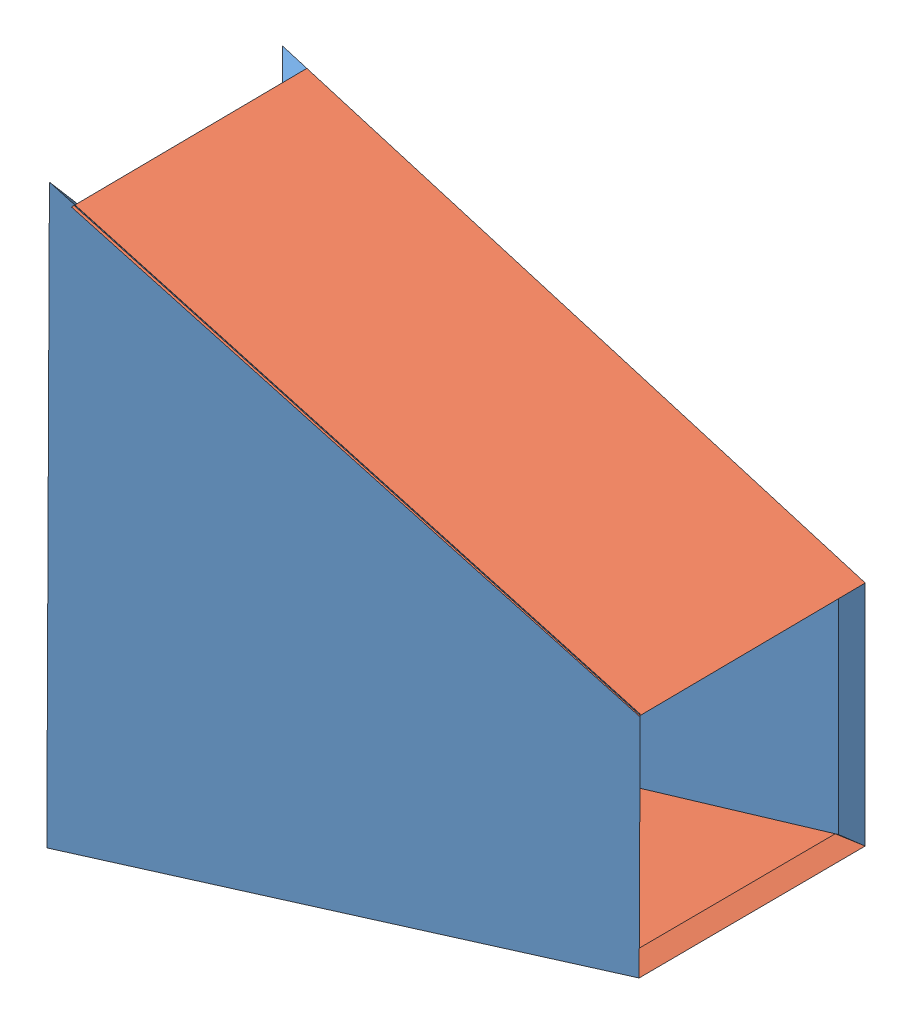
SolidWorks assembly Baugruppe2, configuration Standard. Lengths in mm.
Overall size (436.05 429.6 180.8).
4 component instances, 2 part files, 8 mates.
Components (placement in the parent):
- Gehäseseite1-2: Gehäseseite1 [Standard] at (252.3997 -5.8404 429.7143) size (434.71 429.2 10)
- Gehäseseite2-2: Gehäseseite2 [Standard] at (253.0555 78.9641 514.7116) x (0.958288 -0.285691 -0.008051) z (-0.285701 -0.958319 0) size (434.71 177 10)
- Gehäseseite2-3: Gehäseseite2 [Standard] at (253.0555 -90.6449 514.7116) x (0.958288 0.285691 -0.008051) z (-0.285701 0.958319 0) size (434.71 177 10)
- Gehäseseite1-3: Gehäseseite1 [Standard] at (253.7083 -5.4503 599.3178) x (0.999881 -0.000035 -0.01543) z (-0.01543 -0.0046 -0.99987) size (434.71 429.2 10)
Mates (geometry in assembly coordinates):
- Deckungsgleich13: coincident: line of Gehäseseite1-2 through (252.3997 79.1596 429.7143) axis (-0.958319 0.285701 0); line of Gehäseseite2-2 through (-164.2088 203.3617 429.7143) axis (0.958319 -0.285701 0)
- Deckungsgleich14: coincident: point of Gehäseseite1-2; point of Gehäseseite2-2
- Deckungsgleich15: coincident: line of Gehäseseite1-2 through (-182.3146 -220.4404 429.7143) axis (0.958319 0.285701 0); line of Gehäseseite2-3 through (252.3997 -90.8404 429.7143) axis (-0.958319 -0.285701 0)
- Deckungsgleich16: coincident: line of Gehäseseite1-2 through (-172.3146 -207.0242 439.7143) axis (0.958319 0.285701 0); line of Gehäseseite2-3 through (240.0364 -84.0913 439.7143) axis (-0.958319 -0.285701 0)
- Deckungsgleich17: coincident: point of Gehäseseite1-2; point of Gehäseseite2-3
- Deckungsgleich19: coincident: line of Gehäseseite2-3 through (-162.8431 -214.6355 606.7086) axis (0.958195 0.285664 -0.016101); line of Gehäseseite1-3 through (253.7113 -90.4494 599.7088) axis (-0.958195 -0.285664 0.016101)
- Deckungsgleich20: coincident: line of Gehäseseite2-3 through (-156.195 -202.2185 596.5476) axis (0.958195 0.285664 -0.016101); line of Gehäseseite1-3 through (243.558 -83.0414 589.8301) axis (-0.958195 -0.285664 0.016101)
- Deckungsgleich21: coincident: point of Gehäseseite2-3; point of Gehäseseite1-3
